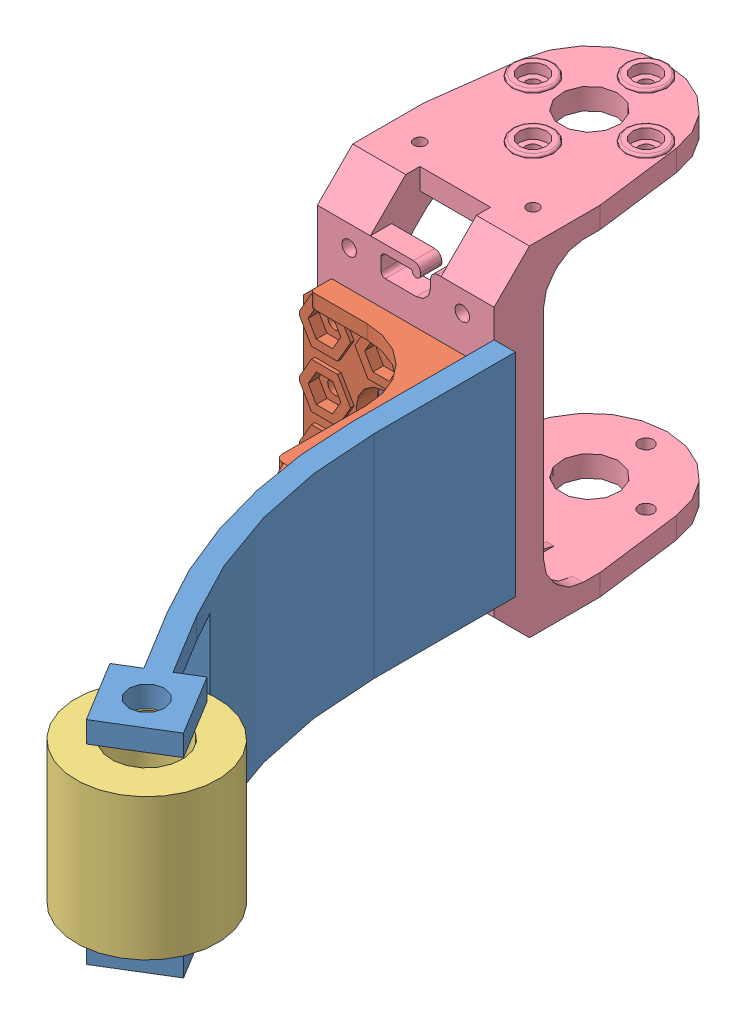
SolidWorks assembly essai_assemblage_pince_1, configuration Default. Lengths in mm.
Overall size (54.97 48.81 116.12).
4 component instances, 4 part files, 8 mates.
Components (placement in the parent):
- essai_pince_4-1: essai_pince_4 [Default] at (-8.4781 -11.6289 -22.4125) size (26.21 30 75.36)
- F9ORG-1: F9ORG [Défaut] at (-8.4781 3.3711 -42.4125) x (1 0 0) z (0 0 -1) size (24 24 30)
- Rouleau_D20_H20-1: Rouleau_D20_H20 [Default] at (10.8633 -6.6289 26.0741) x (0.997859 0 -0.0654) z (0.0654 0 0.997859) size (20 20 20)
- F2-1: F2 [Défaut] at (-20.9781 3.3711 -68.4125) x (0 1 0) z (0 0 1) size (48.81 25 37)
Mates (geometry in assembly coordinates):
- Coïncidente1: coincident: plane of essai_pince_4-1 through (-8.4781 18.3711 -22.4125) normal (-1 0 0); plane of F9ORG-1 through (-8.4781 15.3711 -42.4125) normal (1 0 0)
- Coïncidente2: coincident: plane of essai_pince_4-1 through (-8.4781 18.3711 -42.4125) normal (0 0 -1); plane of F9ORG-1 through (-33.4781 15.3711 -42.4125) normal (0 0 -1)
- Coaxiale1: concentric: cylinder of essai_pince_4-1; cylinder of Rouleau_D20_H20-1
- Distance1: distance = 2 mm: plane of Rouleau_D20_H20-1 through (10.8633 13.3711 26.0741) normal (0 1 0); plane of essai_pince_4-1 through (48.9286 15.3711 8.7024) normal (0 -1 0)
- Distance2: distance = 3 mm aligned: plane of F9ORG-1 through (-8.4781 15.3711 -42.4125) normal (0 1 0); plane of essai_pince_4-1 through (61.5219 18.3711 -22.4125) normal (0 1 0)
- Coïncidente3: coincident: plane of F9ORG-1 through (-33.4781 15.3711 -42.4125) normal (0 0 -1); plane of ? through (-33.4781 -11.318 -42.4125) normal (0 0 1)
- Coïncidente4: coincident: plane of F9ORG-1 through (-8.4781 15.3711 -42.4125) normal (1 0 0); plane of ? through (-8.4781 -11.318 -42.4125) normal (1 0 0)
- Coaxiale3: concentric anti-aligned: cylinder of F9ORG-1; cylinder of ?
